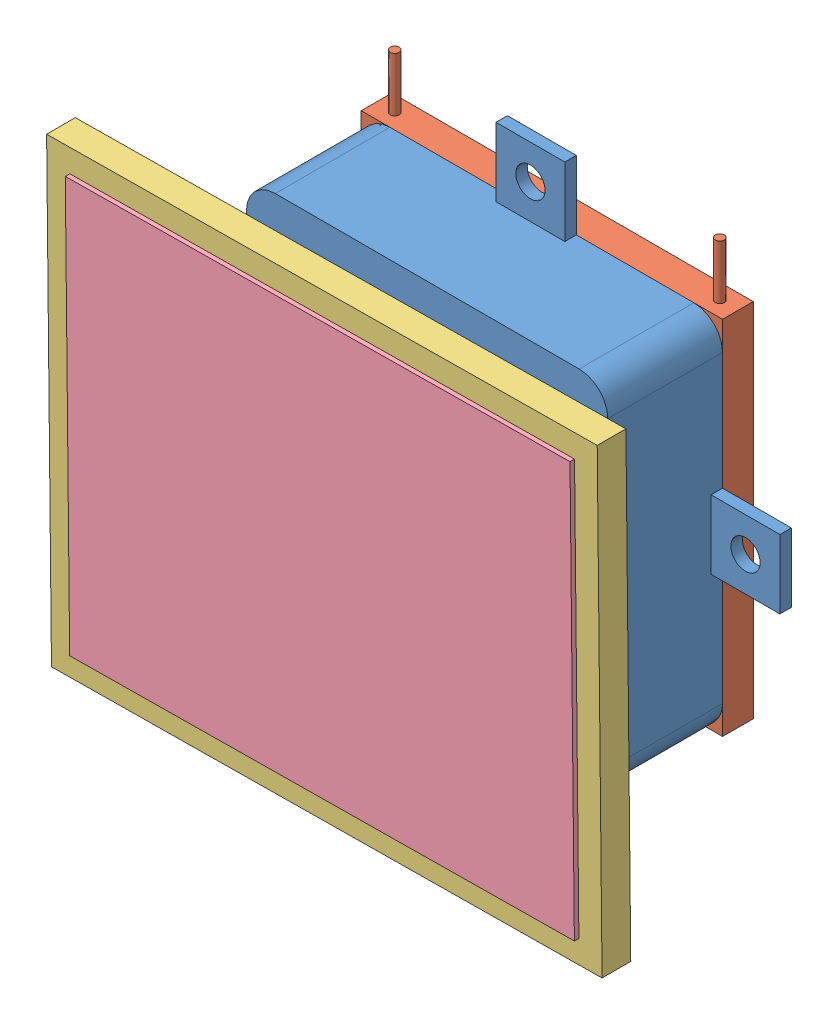
SolidWorks assembly Open PCR Assem, configuration Default. Lengths in mm.
Overall size (61.49 55.24 28.32).
4 component instances, 4 part files, 6 mates.
Components (placement in the parent):
- Main Heating Block-1: Main Heating Block [Default] at (35.8711 5.4929 -8.1802) size (55.24 55.24 12.7)
- VT-127-1.4-1.15-71 Peltier-1: VT-127-1.4-1.15-71 Peltier [Default] at (34.0692 -7.0043 -11.5802) x (1 0 0) z (0 -1 0) size (40 3.4 46)
- Top Plate Alum-1: Top Plate Alum [Default] at (7.6144 21.5997 13.0672) x (-0.010575 0.999944 0) z (0.999944 0.010575 0) size (50.8 3.17 60.96)
- Kapton Heater-1: Kapton Heater [Default] at (15.7897 -0.9829 16.7422) x (0.999944 0.010575 0) z (-0.010575 0.999944 0) size (55.88 0.5 45.72)
Mates (geometry in assembly coordinates):
- Coincident1: coincident anti-aligned: plane of Main Heating Block-1 through (-16.6027 -19.9449 -8.1802) normal (0 0 -1); plane of VT-127-1.4-1.15-71 Peltier-1 through (-16.6027 -19.9449 -8.1802) normal (0 0 1)
- Coincident2: coincident aligned: line of Main Heating Block-1 through (20.2223 20.0551 -8.1802) axis (-1 0 0); line of VT-127-1.4-1.15-71 Peltier-1 through (23.3973 20.0551 -8.1802) axis (-1 0 0)
- Coincident3: coincident aligned: line of Main Heating Block-1 through (-16.6027 16.8801 -8.1802) axis (0 -1 0); line of VT-127-1.4-1.15-71 Peltier-1 through (-16.6027 20.0551 -8.1802) axis (0 -1 0)
- Coincident15: coincident anti-aligned: plane of Top Plate Alum-1 through (34.4823 -25.3436 16.2422) normal (0 0 1); plane of Kapton Heater-1 through (-24.4447 22.2959 16.2422) normal (0 0 -1)
- Distance5: distance = 2.54 mm aligned: plane of Kapton Heater-1 through (-24.4447 22.2959 16.2422) normal (-0.010575 0.999944 0); plane of Top Plate Alum-1 through (-27.0114 24.8089 16.2422) normal (-0.010575 0.999944 0)
- Distance6: distance = 2.54 mm aligned: plane of Kapton Heater-1 through (31.9156 -22.8306 16.2422) normal (0.999944 0.010575 0); plane of Top Plate Alum-1 through (34.4823 -25.3436 16.2422) normal (0.999944 0.010575 0)
